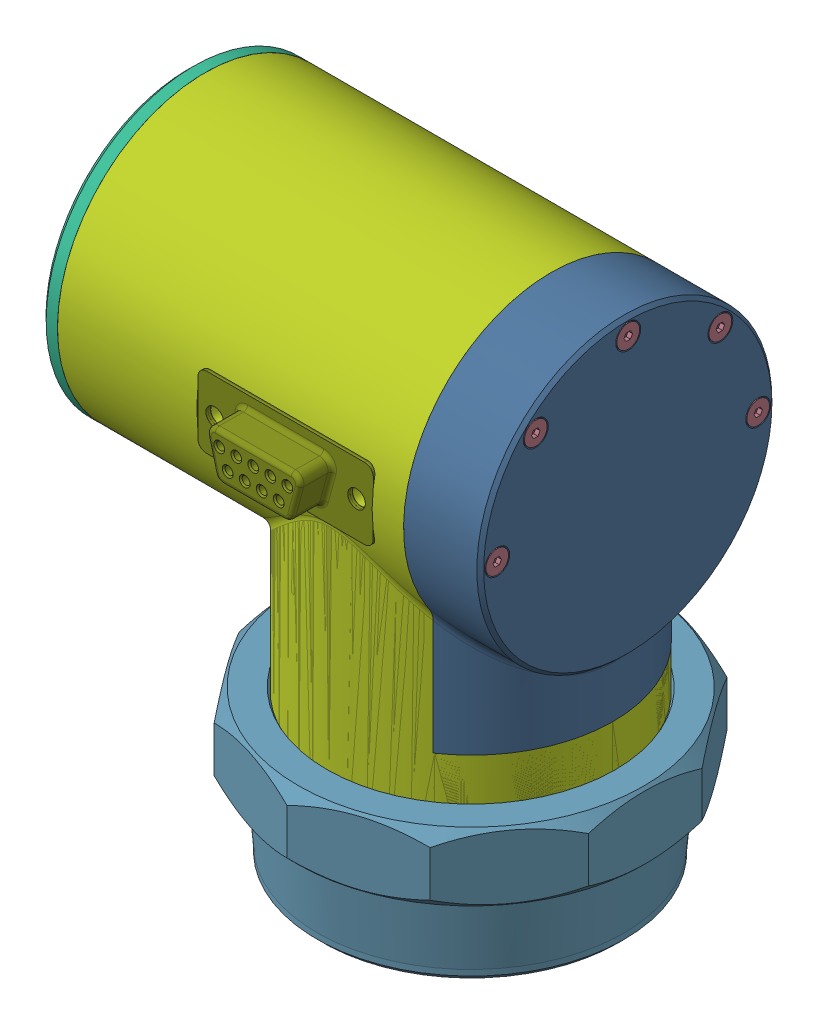
SolidWorks assembly link_2_part_2, configuration 00. Lengths in mm.
Overall size (83.78 107.15 73.54).
35 component instances, 16 part files, 93 mates.
Components (placement in the parent):
- shaft_2-1: shaft_2 [00] x (1 0 0) z (0 0.707107 0.707107) size (31 32 32)
- bearing_6905-2RS-1: bearing_6905-2RS [00] at (-25 0 0) size (9 42 42)
- sleave_internal_2-1: sleave_internal_2 [00] at (-16 0 0) size (3 29 29)
- sleave_external_2-2: sleave_external_2 [00] at (-16 0 0) size (3 42 42)
- bearing_6905-2RS-2: bearing_6905-2RS [00] at (-13 0 0) size (9 42 42)
- servo_flange_2-1: servo_flange_2 [По умолчанию] at (-2.5 0 0) x (0 -1 0) z (0 0 1) size (20 4.5 20)
- bearing_cover_2-1: bearing_cover_2 [00] at (-28 0 0) x (1 0 0) z (0 0.709921 0.704282) size (3.19 52 52)
- case_2_part_2-3: case_2_part_2 [00] at (-25 0 0) x (1 0 0) z (0 0.003987 0.999992) size (72 93 52)
- servo_MG995-2: servo_MG995 [По умолчанию] at (42 -9.9999 0.0399) x (0 0.999992 -0.003987) z (-1 0 0) size (55.5 20 44.57)
- screw_M2x10(DIN7991)_2_part_2-2: screw_M2x10(DIN7991)_2_part_2 [Default] at (-26.8 22.9998 -0.0917) x (1 0 0) z (0 -0.003987 -0.999992) size (10 4 4)
- case_cover_2_part_2-2: case_cover_2_part_2 [00] at (22 0 0) x (0 -0.999992 0.003987) z (0 0.003987 0.999992) size (63 17.67 52)
- servo_lock_2-1: servo_lock_2 [00] at (8 0 0) x (0 -0.003987 -0.999992) z (1 0 0) size (50 59.91 34)
- bolt_M3x8(DIN912)-1: bolt_M3x8(DIN912) [По умолчанию] at (17 14.0198 4.9441) x (0 -0.003987 -0.999992) z (1 0 0) size (4.6 4.6 10)
- screw_M2x10(DIN7991)_2_part_2-13: screw_M2x10(DIN7991)_2_part_2 [Default] at (-26.8 16.3282 16.1985) x (1 0 0) z (0 -0.003987 -0.999992) size (10 4 4)
- screw_M2x10(DIN7991)_2_part_2-14: screw_M2x10(DIN7991)_2_part_2 [Default] at (-26.8 0.0917 22.9998) x (1 0 0) z (0 -0.003987 -0.999992) size (10 4 4)
- screw_M2x10(DIN7991)_2_part_2-15: screw_M2x10(DIN7991)_2_part_2 [Default] at (-26.8 -16.1985 16.3282) x (1 0 0) z (0 -0.003987 -0.999992) size (10 4 4)
- screw_M2x10(DIN7991)_2_part_2-16: screw_M2x10(DIN7991)_2_part_2 [Default] at (-26.8 -22.9998 0.0917) x (1 0 0) z (0 -0.003987 -0.999992) size (10 4 4)
- screw_M2x10(DIN7991)_2_part_2-17: screw_M2x10(DIN7991)_2_part_2 [Default] at (-26.8 -16.3282 -16.1985) x (1 0 0) z (0 -0.003987 -0.999992) size (10 4 4)
- screw_M2x10(DIN7991)_2_part_2-18: screw_M2x10(DIN7991)_2_part_2 [Default] at (-26.8 -0.0917 -22.9998) x (1 0 0) z (0 -0.003987 -0.999992) size (10 4 4)
- screw_M2x10(DIN7991)_2_part_2-19: screw_M2x10(DIN7991)_2_part_2 [Default] at (-26.8 16.1985 -16.3282) x (1 0 0) z (0 -0.003987 -0.999992) size (10 4 4)
- bolt_M3x8(DIN912)-10: bolt_M3x8(DIN912) [По умолчанию] at (2 -7 0) x (0 -0.868012 -0.496543) z (1 0 0) size (4.6 4.6 10)
- bolt_M3x8(DIN912)-11: bolt_M3x8(DIN912) [По умолчанию] at (2 0 7) x (0 -0.868012 -0.496543) z (1 0 0) size (4.6 4.6 10)
- bolt_M3x8(DIN912)-12: bolt_M3x8(DIN912) [По умолчанию] at (2 7 0) x (0 -0.868012 -0.496543) z (1 0 0) size (4.6 4.6 10)
- bolt_M3x8(DIN912)-13: bolt_M3x8(DIN912) [По умолчанию] at (2 0 -7) x (0 -0.868012 -0.496543) z (1 0 0) size (4.6 4.6 10)
- bolt_M3x8(DIN912)-15: bolt_M3x8(DIN912) [По умолчанию] at (17 13.98 -5.0558) x (0 -0.003987 -0.999992) z (1 0 0) size (4.6 4.6 10)
- bolt_M3x8(DIN912)-16: bolt_M3x8(DIN912) [По умолчанию] at (17 -33.9798 5.1355) x (0 -0.003987 -0.999992) z (1 0 0) size (4.6 4.6 10)
- bolt_M3x8(DIN912)-17: bolt_M3x8(DIN912) [По умолчанию] at (17 -34.0197 -4.8644) x (0 -0.003987 -0.999992) z (1 0 0) size (4.6 4.6 10)
- screw_M2x16(DIN7991)_2_part_2-6: screw_M2x16(DIN7991)_2_part_2 [Default] at (48.3 0.0917 22.9998) x (-1 0 0) z (0 -0.003987 -0.999992) size (16 4 4)
- screw_M2x16(DIN7991)_2_part_2-7: screw_M2x16(DIN7991)_2_part_2 [Default] at (48.3 16.3282 16.1985) x (-1 0 0) z (0 -0.003987 -0.999992) size (16 4 4)
- screw_M2x16(DIN7991)_2_part_2-8: screw_M2x16(DIN7991)_2_part_2 [Default] at (48.3 22.9998 -0.0917) x (-1 0 0) z (0 -0.003987 -0.999992) size (16 4 4)
- screw_M2x16(DIN7991)_2_part_2-9: screw_M2x16(DIN7991)_2_part_2 [Default] at (48.3 16.1985 -16.3282) x (-1 0 0) z (0 -0.003987 -0.999992) size (16 4 4)
- screw_M2x16(DIN7991)_2_part_2-10: screw_M2x16(DIN7991)_2_part_2 [Default] at (48.3 -0.0917 -22.9998) x (-1 0 0) z (0 -0.003987 -0.999992) size (16 4 4)
- collet_nut_2_part_2-1: collet_nut_2_part_2 [По умолчанию] at (22 -56.1996 0.2241) x (-1 0 0) z (0 0.003987 0.999992) size (61.55 26.55 68.27)
- circlip for shafts normal_din-1: circlip for shafts normal_din [Circlip DIN 471 - 25 x 1.2] at (-4 0 0) x (0 0.144431 0.989515) z (-1 0 0) size (28.33 31.3 1.2)
- A_DB9-1: A_DB9 [По умолчанию] at (5.9719 -16.7195 3.89) x (1 0 0) z (0 0.003987 0.999992) size (30.9 12.5 15.5)
Mates (geometry in assembly coordinates):
- Совпадение1: coincident anti-aligned: plane of shaft_2-1 through (-25 8.8388 -8.8388) normal (1 0 0); plane of bearing_6905-2RS-1 through (-25 15.05 0) normal (-1 0 0)
- Концентричный1: concentric aligned: cylinder of shaft_2-1 through (0 0 0) axis (-1 0 0) radius 12.5; cylinder of bearing_6905-2RS-1 through (-25 0 0) axis (-1 0 0) radius 12.5
- Концентричный2: concentric aligned: cylinder of shaft_2-1 through (0 0 0) axis (-1 0 0) radius 12.5; cylinder of sleave_internal_2-1 through (-16 0 0) axis (-1 0 0) radius 12.5
- Концентричный4: concentric aligned: cylinder of shaft_2-1 through (0 0 0) axis (-1 0 0) radius 12.5; cylinder of sleave_external_2-2 through (-16 0 0) axis (-1 0 0) radius 19
- Концентричный5: concentric aligned: cylinder of shaft_2-1 through (0 0 0) axis (-1 0 0) radius 12.5; cylinder of bearing_6905-2RS-2 through (-13 0 0) axis (-1 0 0) radius 12.5
- Концентричный13: concentric anti-aligned: cylinder of shaft_2-1 through (0 0 0) axis (1 0 0) radius 10; cylinder of servo_flange_2-1 through (0 0 0) axis (-1 0 0) radius 2.95
- Совпадение15: coincident anti-aligned: plane of shaft_2-1 through (-2.5 7.0711 -7.0711) normal (1 0 0); plane of servo_flange_2-1 through (-2.5 0 0) normal (-1 0 0)
- Концентричный16: concentric aligned: cylinder of bearing_cover_2-1 through (-28 22.9998 -0.0917) axis (-1 0 0) radius 1.2; cylinder of case_2_part_2-3 through (-25 22.9998 -0.0917) axis (-1 0 0) radius 0.8
- Концентричный17: concentric aligned: cylinder of bearing_cover_2-1 through (-28 0 0) axis (-1 0 0) radius 26; cylinder of case_2_part_2-3 through (-25 0 0) axis (-1 0 0) radius 26
- Совпадение18: coincident anti-aligned: plane of bearing_cover_2-1 through (-25 18.3113 -18.4579) normal (1 0 0); plane of case_2_part_2-3 through (-25 25.9998 -0.1037) normal (-1 0 0)
- Концентричный18: concentric anti-aligned: cylinder of servo_flange_2-1 through (0 0 0) axis (-1 0 0) radius 2.95; cylinder of servo_MG995-2 through (1.2 0 0) axis (1 0 0) radius 2
- Совпадение22: coincident aligned: plane of bearing_cover_2-1 through (-28 13.3814 -13.4885) normal (-1 0 0); plane of screw_M2x10(DIN7991)_2_part_2-2 through (-28 20.9998 -0.0837) normal (-1 0 0)
- Совпадение27: coincident anti-aligned: plane of case_2_part_2-3 through (36 -90.2623 26.3601) normal (1 0 0); plane of case_cover_2_part_2-2 through (36 0 0) normal (-1 0 0)
- Совпадение29: coincident anti-aligned: plane of servo_MG995-2 through (13 10.3029 0.7089) normal (-1 0 0); plane of servo_lock_2-1 through (13 0 0) normal (1 0 0)
- Совпадение30: coincident anti-aligned: plane of servo_MG995-2 through (12.7 10.0378 9.4601) normal (0 0.999992 -0.003987); plane of servo_lock_2-1 through (13 10.0398 9.96) normal (0 -0.999992 0.003987)
- Совпадение31: coincident anti-aligned: plane of servo_MG995-2 through (15.3 -29.4599 10.1175) normal (0 0.003987 0.999992); plane of servo_lock_2-1 through (13 -29.9599 10.1195) normal (0 -0.003987 -0.999992)
- Концентричный27: concentric anti-aligned: cylinder of servo_lock_2-1 through (13 14.0198 4.9441) axis (1 0 0) radius 1.25; cylinder of bolt_M3x8(DIN912)-1 through (17 14.0198 4.9441) axis (-1 0 0) radius 1.5
- Совпадение33: coincident anti-aligned: plane of servo_MG995-2 through (15 10.262 -9.541) normal (1 0 0); plane of bolt_M3x8(DIN912)-1 through (15 16.3198 4.935) normal (-1 0 0)
- Параллельность1: parallel anti-aligned: axis of servo_MG995-2 through (15.3 -30.2619 9.6207) axis (0 -0.003987 -0.999992); line of screw_M2x10(DIN7991)_2_part_2-2 through (-28 22.3483 -0.4644) axis (0 0.003987 0.999992)
- Концентричный29: concentric aligned: cylinder of bearing_cover_2-1 through (-28 22.9998 -0.0917) axis (-1 0 0) radius 1.2; cylinder of screw_M2x10(DIN7991)_2_part_2-2 through (-28 22.9998 -0.0917) axis (-1 0 0) radius 1
- Совпадение38: coincident aligned: plane of bearing_cover_2-1 through (-28 13.3814 -13.4885) normal (-1 0 0); plane of screw_M2x10(DIN7991)_2_part_2-13 through (-28 14.3282 16.2065) normal (-1 0 0)
- Параллельность5: parallel anti-aligned: axis of servo_MG995-2 through (15.3 -30.2619 9.6207) axis (0 -0.003987 -0.999992); line of screw_M2x10(DIN7991)_2_part_2-13 through (-28 15.6767 15.8258) axis (0 0.003987 0.999992)
- Концентричный33: concentric aligned: cylinder of bearing_cover_2-1 through (-28 16.3282 16.1985) axis (-1 0 0) radius 1.2; cylinder of screw_M2x10(DIN7991)_2_part_2-13 through (-28 16.3282 16.1985) axis (-1 0 0) radius 1
- Совпадение39: coincident aligned: plane of bearing_cover_2-1 through (-28 13.3814 -13.4885) normal (-1 0 0); plane of screw_M2x10(DIN7991)_2_part_2-14 through (-28 -1.9083 23.0078) normal (-1 0 0)
- Параллельность6: parallel anti-aligned: axis of servo_MG995-2 through (15.3 -30.2619 9.6207) axis (0 -0.003987 -0.999992); line of screw_M2x10(DIN7991)_2_part_2-14 through (-28 -0.5598 22.6271) axis (0 0.003987 0.999992)
- Концентричный34: concentric aligned: cylinder of bearing_cover_2-1 through (-28 0.0917 22.9998) axis (-1 0 0) radius 1.2; cylinder of screw_M2x10(DIN7991)_2_part_2-14 through (-28 0.0917 22.9998) axis (-1 0 0) radius 1
- Совпадение40: coincident aligned: plane of bearing_cover_2-1 through (-28 13.3814 -13.4885) normal (-1 0 0); plane of screw_M2x10(DIN7991)_2_part_2-15 through (-28 -18.1985 16.3361) normal (-1 0 0)
- Параллельность7: parallel anti-aligned: axis of servo_MG995-2 through (15.3 -30.2619 9.6207) axis (0 -0.003987 -0.999992); line of screw_M2x10(DIN7991)_2_part_2-15 through (-28 -16.85 15.9555) axis (0 0.003987 0.999992)
- Концентричный37: concentric aligned: cylinder of bearing_cover_2-1 through (-28 -16.1985 16.3282) axis (-1 0 0) radius 1.2; cylinder of screw_M2x10(DIN7991)_2_part_2-15 through (-28 -16.1985 16.3282) axis (-1 0 0) radius 1
- Совпадение41: coincident aligned: plane of bearing_cover_2-1 through (-28 13.3814 -13.4885) normal (-1 0 0); plane of screw_M2x10(DIN7991)_2_part_2-16 through (-28 -24.9998 0.0997) normal (-1 0 0)
- Параллельность8: parallel anti-aligned: axis of servo_MG995-2 through (15.3 -30.2619 9.6207) axis (0 -0.003987 -0.999992); line of screw_M2x10(DIN7991)_2_part_2-16 through (-28 -23.6513 -0.281) axis (0 0.003987 0.999992)
- Концентричный38: concentric aligned: cylinder of bearing_cover_2-1 through (-28 -22.9998 0.0917) axis (-1 0 0) radius 1.2; cylinder of screw_M2x10(DIN7991)_2_part_2-16 through (-28 -22.9998 0.0917) axis (-1 0 0) radius 1
- Совпадение42: coincident aligned: plane of bearing_cover_2-1 through (-28 13.3814 -13.4885) normal (-1 0 0); plane of screw_M2x10(DIN7991)_2_part_2-17 through (-28 -18.3282 -16.1905) normal (-1 0 0)
- Параллельность9: parallel anti-aligned: axis of servo_MG995-2 through (15.3 -30.2619 9.6207) axis (0 -0.003987 -0.999992); line of screw_M2x10(DIN7991)_2_part_2-17 through (-28 -16.9797 -16.5712) axis (0 0.003987 0.999992)
- Концентричный39: concentric aligned: cylinder of bearing_cover_2-1 through (-28 -16.3282 -16.1985) axis (-1 0 0) radius 1.2; cylinder of screw_M2x10(DIN7991)_2_part_2-17 through (-28 -16.3282 -16.1985) axis (-1 0 0) radius 1
- Совпадение43: coincident aligned: plane of bearing_cover_2-1 through (-28 13.3814 -13.4885) normal (-1 0 0); plane of screw_M2x10(DIN7991)_2_part_2-18 through (-28 -2.0917 -22.9918) normal (-1 0 0)
- Параллельность10: parallel anti-aligned: axis of servo_MG995-2 through (15.3 -30.2619 9.6207) axis (0 -0.003987 -0.999992); line of screw_M2x10(DIN7991)_2_part_2-18 through (-28 -0.7432 -23.3725) axis (0 0.003987 0.999992)
- Концентричный40: concentric aligned: cylinder of bearing_cover_2-1 through (-28 -0.0917 -22.9998) axis (-1 0 0) radius 1.2; cylinder of screw_M2x10(DIN7991)_2_part_2-18 through (-28 -0.0917 -22.9998) axis (-1 0 0) radius 1
- Совпадение44: coincident aligned: plane of bearing_cover_2-1 through (-28 13.3814 -13.4885) normal (-1 0 0); plane of screw_M2x10(DIN7991)_2_part_2-19 through (-28 14.1985 -16.3202) normal (-1 0 0)
- Параллельность11: parallel anti-aligned: axis of servo_MG995-2 through (15.3 -30.2619 9.6207) axis (0 -0.003987 -0.999992); line of screw_M2x10(DIN7991)_2_part_2-19 through (-28 15.547 -16.7009) axis (0 0.003987 0.999992)
- Концентричный41: concentric aligned: cylinder of bearing_cover_2-1 through (-28 16.1985 -16.3282) axis (-1 0 0) radius 1.2; cylinder of screw_M2x10(DIN7991)_2_part_2-19 through (-28 16.1985 -16.3282) axis (-1 0 0) radius 1
- Параллельность14: parallel aligned: line of servo_MG995-2 through (41.0879 9.8845 -6.9516) axis (0 0.003987 0.999992); line of bolt_M3x8(DIN912)-1 through (17 15.2669 4.2175) axis (0 0.003987 0.999992)
- Параллельность19: parallel anti-aligned: plane of case_2_part_2-3 through (22 -36.9997 0.1475) normal (0 0.999992 -0.003987); plane of case_cover_2_part_2-2 through (47 -36.9997 0.1475) normal (0 -0.999992 0.003987)
- Концентричный46: concentric aligned: cylinder of case_cover_2_part_2-2 through (22 0 0) axis (-1 0 0) radius 25; cylinder of servo_lock_2-1 through (42 0 0) axis (-1 0 0) radius 25
- Концентричный47: concentric aligned: circle of case_2_part_2-3; cylinder of servo_lock_2-1 through (42 0.0917 22.9998) axis (1 0 0) radius 1.25
- Совпадение54: coincident anti-aligned: plane of case_2_part_2-3 through (36 -90.2623 26.3601) normal (1 0 0); plane of servo_lock_2-1 through (36 0 0) normal (-1 0 0)
- Концентричный48: concentric aligned: cylinder of servo_flange_2-1 through (0 -7 0) axis (-1 0 0) radius 1.5; cylinder of bolt_M3x8(DIN912)-10 through (2 -7 0) axis (-1 0 0) radius 1.5
- Совпадение55: coincident anti-aligned: plane of servo_flange_2-1 through (0 0 0) normal (1 0 0); circle of bolt_M3x8(DIN912)-10
- Параллельность20: parallel aligned: line of servo_lock_2-1 through (8 16.96 -10.0677) axis (0 0.003987 0.999992); line of bolt_M3x8(DIN912)-10 through (2 -5.7529 -0.7267) axis (0 0.003987 0.999992)
- Совпадение57: coincident anti-aligned: plane of servo_flange_2-1 through (0 0 0) normal (1 0 0); circle of bolt_M3x8(DIN912)-11
- Параллельность21: parallel aligned: line of servo_lock_2-1 through (8 16.96 -10.0677) axis (0 0.003987 0.999992); line of bolt_M3x8(DIN912)-11 through (2 1.2471 6.2733) axis (0 0.003987 0.999992)
- Концентричный49: concentric aligned: cylinder of servo_flange_2-1 through (0 0 7) axis (-1 0 0) radius 1.5; cylinder of bolt_M3x8(DIN912)-11 through (2 0 7) axis (-1 0 0) radius 1.5
- Совпадение58: coincident anti-aligned: plane of servo_flange_2-1 through (0 0 0) normal (1 0 0); circle of bolt_M3x8(DIN912)-12
- Параллельность22: parallel aligned: line of servo_lock_2-1 through (8 16.96 -10.0677) axis (0 0.003987 0.999992); line of bolt_M3x8(DIN912)-12 through (2 8.2471 -0.7267) axis (0 0.003987 0.999992)
- Концентричный50: concentric aligned: cylinder of servo_flange_2-1 through (0 7 0) axis (-1 0 0) radius 1.5; cylinder of bolt_M3x8(DIN912)-12 through (2 7 0) axis (-1 0 0) radius 1.5
- Совпадение59: coincident anti-aligned: plane of servo_flange_2-1 through (0 0 0) normal (1 0 0); circle of bolt_M3x8(DIN912)-13
- Параллельность23: parallel aligned: line of servo_lock_2-1 through (8 16.96 -10.0677) axis (0 0.003987 0.999992); line of bolt_M3x8(DIN912)-13 through (2 1.2471 -7.7267) axis (0 0.003987 0.999992)
- Концентричный51: concentric aligned: cylinder of servo_flange_2-1 through (0 0 -7) axis (-1 0 0) radius 1.5; cylinder of bolt_M3x8(DIN912)-13 through (2 0 -7) axis (-1 0 0) radius 1.5
- Совпадение61: coincident anti-aligned: plane of servo_MG995-2 through (15 10.262 -9.541) normal (1 0 0); plane of bolt_M3x8(DIN912)-15 through (15 16.2799 -5.065) normal (-1 0 0)
- Параллельность25: parallel aligned: line of servo_MG995-2 through (41.0879 9.8845 -6.9516) axis (0 0.003987 0.999992); line of bolt_M3x8(DIN912)-15 through (17 15.2271 -5.7824) axis (0 0.003987 0.999992)
- Концентричный52: concentric aligned: cone of servo_lock_2-1 through (13 13.98 -5.0558) axis (-1 0 0); cylinder of bolt_M3x8(DIN912)-15 through (17 13.98 -5.0558) axis (-1 0 0) radius 1.5
- Совпадение62: coincident anti-aligned: plane of servo_MG995-2 through (15 10.262 -9.541) normal (1 0 0); plane of bolt_M3x8(DIN912)-16 through (15 -31.6798 5.1264) normal (-1 0 0)
- Параллельность26: parallel aligned: line of servo_MG995-2 through (41.0879 9.8845 -6.9516) axis (0 0.003987 0.999992); line of bolt_M3x8(DIN912)-16 through (17 -32.7327 4.4089) axis (0 0.003987 0.999992)
- Концентричный53: concentric aligned: cone of servo_lock_2-1 through (13 -33.9798 5.1355) axis (-1 0 0); cylinder of bolt_M3x8(DIN912)-16 through (17 -33.9798 5.1355) axis (-1 0 0) radius 1.5
- Совпадение63: coincident anti-aligned: plane of servo_MG995-2 through (15 10.262 -9.541) normal (1 0 0); plane of bolt_M3x8(DIN912)-17 through (15 -31.7197 -4.8736) normal (-1 0 0)
- Параллельность27: parallel aligned: line of servo_MG995-2 through (41.0879 9.8845 -6.9516) axis (0 0.003987 0.999992); line of bolt_M3x8(DIN912)-17 through (17 -32.7726 -5.5911) axis (0 0.003987 0.999992)
- Концентричный54: concentric anti-aligned: circle of servo_lock_2-1; cylinder of bolt_M3x8(DIN912)-17 through (17 -34.0197 -4.8644) axis (-1 0 0) radius 1.5
- Концентричный55: concentric aligned: cylinder of case_cover_2_part_2-2 through (49.5 0.0917 22.9998) axis (1 0 0) radius 1.2; cylinder of screw_M2x16(DIN7991)_2_part_2-6 through (49.5 0.0917 22.9998) axis (1 0 0) radius 1
- Совпадение65: coincident aligned: plane of case_cover_2_part_2-2 through (49.5 25.9998 -0.1037) normal (1 0 0); plane of screw_M2x16(DIN7991)_2_part_2-6 through (49.5 2.0917 22.9918) normal (1 0 0)
- Параллельность29: parallel aligned: line of servo_lock_2-1 through (8 16.96 -10.0677) axis (0 0.003987 0.999992); line of screw_M2x16(DIN7991)_2_part_2-6 through (49.5 0.7402 22.622) axis (0 0.003987 0.999992)
- Совпадение67: coincident aligned: plane of case_cover_2_part_2-2 through (49.5 25.9998 -0.1037) normal (1 0 0); plane of screw_M2x16(DIN7991)_2_part_2-7 through (49.5 18.3282 16.1905) normal (1 0 0)
- Параллельность30: parallel aligned: line of servo_lock_2-1 through (8 16.96 -10.0677) axis (0 0.003987 0.999992); line of screw_M2x16(DIN7991)_2_part_2-7 through (49.5 16.9767 15.8206) axis (0 0.003987 0.999992)
- Концентричный56: concentric aligned: cylinder of case_cover_2_part_2-2 through (49.5 16.3282 16.1985) axis (1 0 0) radius 1.2; cylinder of screw_M2x16(DIN7991)_2_part_2-7 through (49.5 16.3282 16.1985) axis (1 0 0) radius 1
- Совпадение68: coincident aligned: plane of case_cover_2_part_2-2 through (49.5 25.9998 -0.1037) normal (1 0 0); plane of screw_M2x16(DIN7991)_2_part_2-8 through (49.5 24.9998 -0.0997) normal (1 0 0)
- Параллельность31: parallel aligned: line of servo_lock_2-1 through (8 16.96 -10.0677) axis (0 0.003987 0.999992); line of screw_M2x16(DIN7991)_2_part_2-8 through (49.5 23.6483 -0.4696) axis (0 0.003987 0.999992)
- Концентричный57: concentric aligned: cylinder of case_cover_2_part_2-2 through (49.5 22.9998 -0.0917) axis (1 0 0) radius 1.2; cylinder of screw_M2x16(DIN7991)_2_part_2-8 through (49.5 22.9998 -0.0917) axis (1 0 0) radius 1
- Совпадение69: coincident aligned: plane of case_cover_2_part_2-2 through (49.5 25.9998 -0.1037) normal (1 0 0); plane of screw_M2x16(DIN7991)_2_part_2-9 through (49.5 18.1985 -16.3361) normal (1 0 0)
- Параллельность32: parallel aligned: line of servo_lock_2-1 through (8 16.96 -10.0677) axis (0 0.003987 0.999992); line of screw_M2x16(DIN7991)_2_part_2-9 through (49.5 16.847 -16.706) axis (0 0.003987 0.999992)
- Концентричный58: concentric aligned: cylinder of case_cover_2_part_2-2 through (49.5 16.1985 -16.3282) axis (1 0 0) radius 1.2; cylinder of screw_M2x16(DIN7991)_2_part_2-9 through (49.5 16.1985 -16.3282) axis (1 0 0) radius 1
- Совпадение70: coincident aligned: plane of case_cover_2_part_2-2 through (49.5 25.9998 -0.1037) normal (1 0 0); plane of screw_M2x16(DIN7991)_2_part_2-10 through (49.5 1.9083 -23.0078) normal (1 0 0)
- Параллельность33: parallel aligned: line of servo_lock_2-1 through (8 16.96 -10.0677) axis (0 0.003987 0.999992); line of screw_M2x16(DIN7991)_2_part_2-10 through (49.5 0.5568 -23.3777) axis (0 0.003987 0.999992)
- Концентричный59: concentric aligned: cylinder of case_cover_2_part_2-2 through (49.5 -0.0917 -22.9998) axis (1 0 0) radius 1.2; cylinder of screw_M2x16(DIN7991)_2_part_2-10 through (49.5 -0.0917 -22.9998) axis (1 0 0) radius 1
- Концентричный60: concentric anti-aligned: cylinder of case_2_part_2-3 through (22 25.9998 -0.1037) axis (0 0.999992 -0.003987) radius 25; cone of collet_nut_2_part_2-1 through (22 -44.1996 0.1762) axis (0 -0.999992 0.003987)
- Параллельность34: parallel aligned: plane of case_cover_2_part_2-2 through (49.5 25.9998 -0.1037) normal (1 0 0); plane of collet_nut_2_part_2-1 through (52.7762 -14.2398 -9.9431) normal (1 0 0)
- Концентричный61: concentric anti-aligned: cylinder of shaft_2-1 through (0 0 0) axis (1 0 0) radius 11.8; cylinder of circlip for shafts normal_din-1 through (-2.8 0 0) axis (-1 0 0) radius 11.95
- Совпадение73: coincident anti-aligned: plane of bearing_6905-2RS-2 through (-4 12.5 0) normal (1 0 0); plane of circlip for shafts normal_din-1 through (-4 0 0) normal (-1 0 0)
- Концентричный62: concentric aligned: cylinder of case_2_part_2-3 through (2.5 -0.1037 -26.0008) axis (0 0.003987 0.999992) radius 1.5; cylinder of A_DB9-1 through (2.5 0.0997 24.9998) axis (0 0.003987 0.999992) radius 1.55
- Концентричный63: concentric aligned: cylinder of case_2_part_2-3 through (27.5 -0.1037 -26.0008) axis (0 0.003987 0.999992) radius 1.5; cylinder of A_DB9-1 through (27.5 0.0997 24.9998) axis (0 0.003987 0.999992) radius 1.55
- Совпадение78: coincident anti-aligned: plane of case_2_part_2-3 through (-25 0.0997 24.9998) normal (0 0.003987 0.999992); plane of A_DB9-1 through (15 0.0997 24.9998) normal (0 -0.003987 -0.999992)
- Совпадение79: coincident aligned: cone of case_2_part_2-3 through (22 -56.7995 0.2265) axis (0 -0.999992 0.003987); cone of collet_nut_2_part_2-1 through (22 -68.2295 0.2721) axis (0 -0.999992 0.003987)
- Параллельность35: parallel aligned: plane of case_cover_2_part_2-2 through (49.5 25.9998 -0.1037) normal (1 0 0); plane of collet_nut_2_part_2-1 through (52.7762 -14.2398 -9.9431) normal (1 0 0)
- Концентричный64: concentric anti-aligned: cylinder of shaft_2-1 through (-2.5 7 0) axis (1 0 0) radius 1.25; cylinder of servo_flange_2-1 through (0 7 0) axis (-1 0 0) radius 1.5
- Угол1: planar angle = 0.785398 rad aligned: plane of shaft_2-1 through (0 0 0) normal (0 0.707107 0.707107); plane of assembly through (0 0 0) normal (0 1 0)
